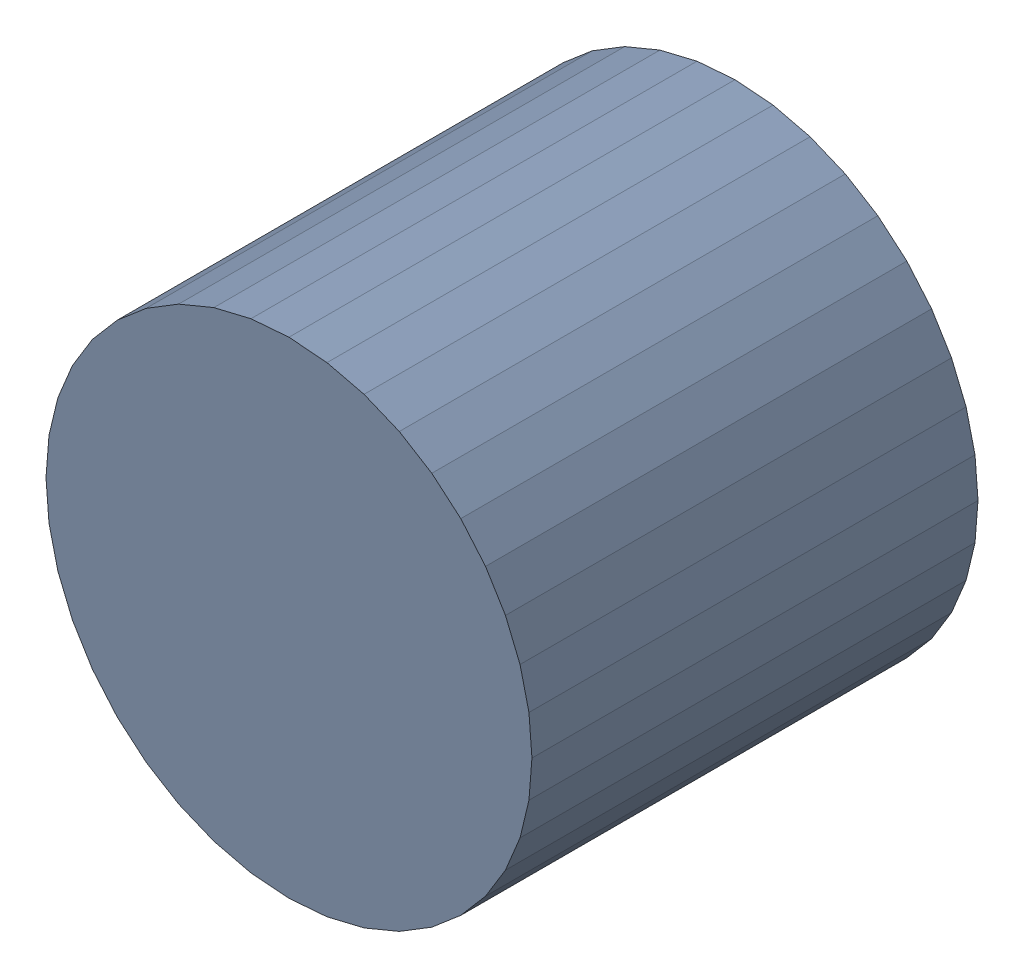
SolidWorks assembly CoutB3Kanaloa_v2.0.0_Power, configuration Default. Lengths in mm.
Overall size (6.32 6.32 5.8).
2 component instances, 1 part files, 0 mates.
Components (placement in the parent):
- 352892112-1: 352892112 [Default] at (83.025 46 0) size (6.32 6.32 5.8)
  - Extruded_11-1: Extruded_11 [Default] at origin size (6.32 6.32 5.8)
